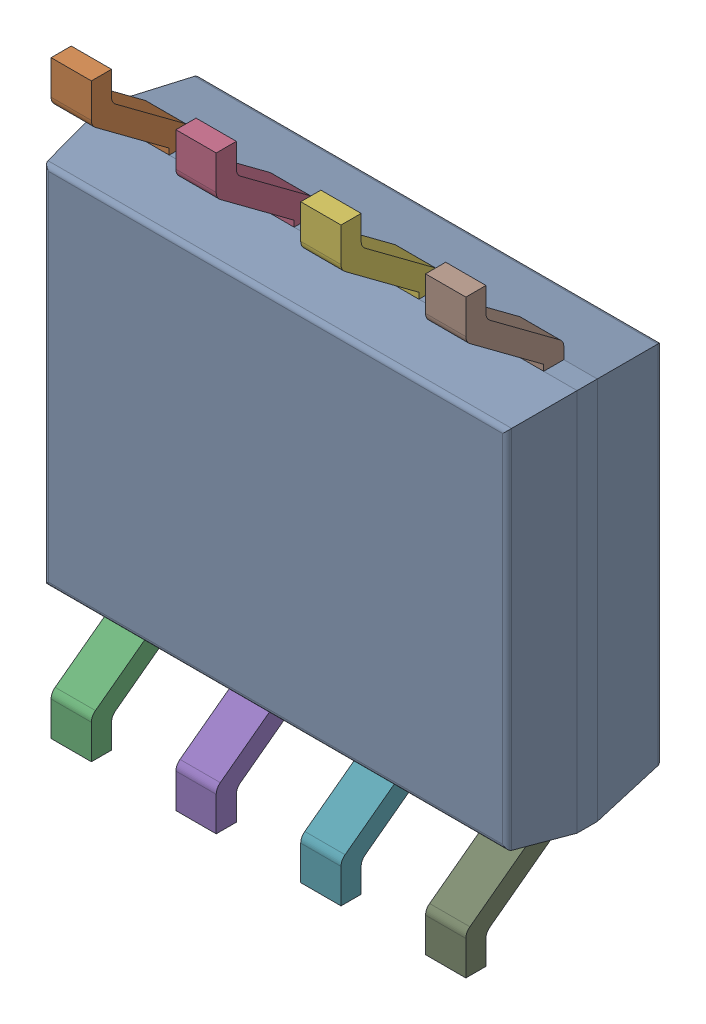
SolidWorks assembly IC4, configuration Default. Lengths in mm.
Overall size (4.9 6 1.75).
3 component instances, 2 part files, 0 mates.
Components (placement in the parent):
- 12042009920-1: 12042009920 [Default] at (123.952 51.054 -1.0914) x (0 -1 0) z (0 0 -1) size (6 4.9 1.75)
  - Body-1: Body [Default] at origin size (3.9 4.9 1.57)
  - PinsArrayLR-1: PinsArrayLR [Default] at origin size (6 4.22 1)
